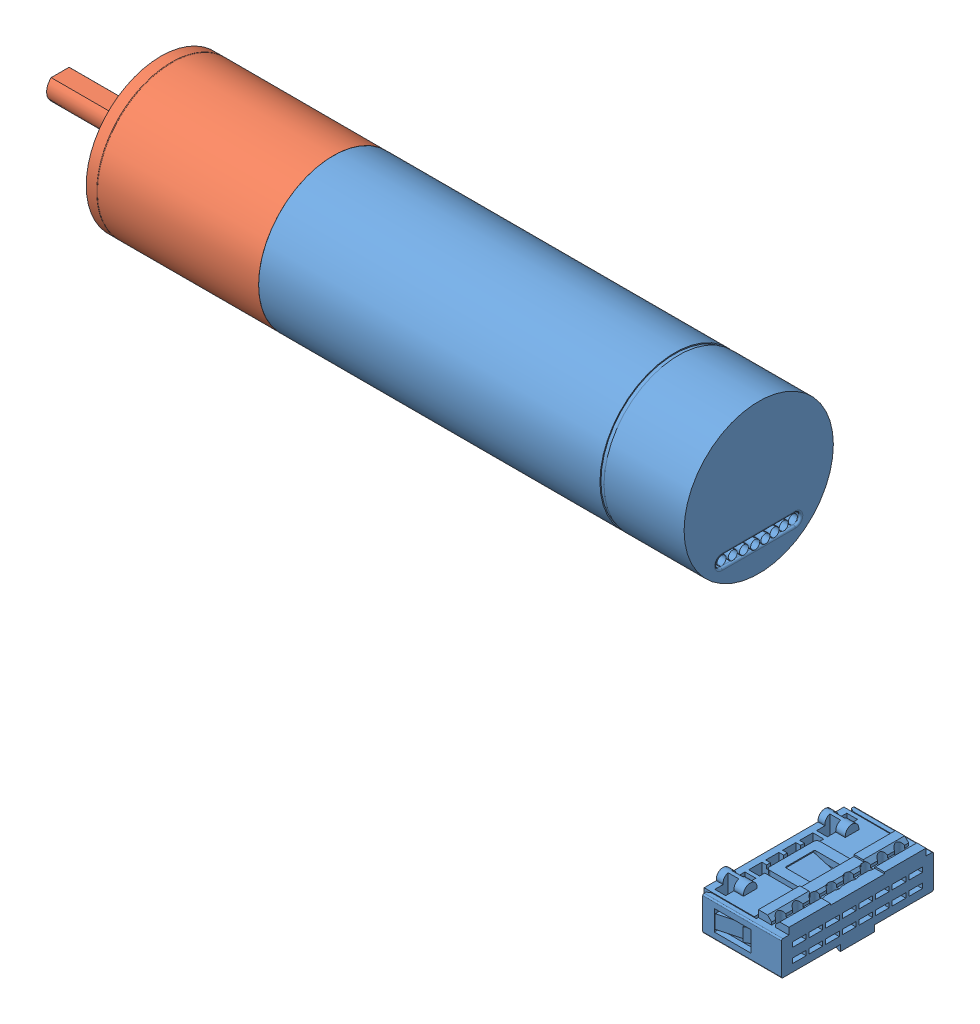
SolidWorks assembly a-Maxon-EC22-386675-v01, configuration 01. Lengths in mm.
Overall size (103.18 22 22).
2 component instances, 2 part files, 1 mates.
Components (placement in the parent):
- z-Motor-Maxon-EC22-386673-v01-1: z-Motor-Maxon-EC22-386673-v01 [01] at origin size (73.23 22 22)
- z-Getriebe-Maxon-GP22C_1-STUFIG-143972-v01-1: z-Getriebe-Maxon-GP22C_1-STUFIG-143972-v01 [01] at (-25.4 0 0) size (40.25 22 22)
Mates (geometry in assembly coordinates):
- Deckungsgleich1: coincident anti-aligned: circle of z-Motor-Maxon-EC22-386673-v01-1; circle of z-Getriebe-Maxon-GP22C_1-STUFIG-143972-v01-1
